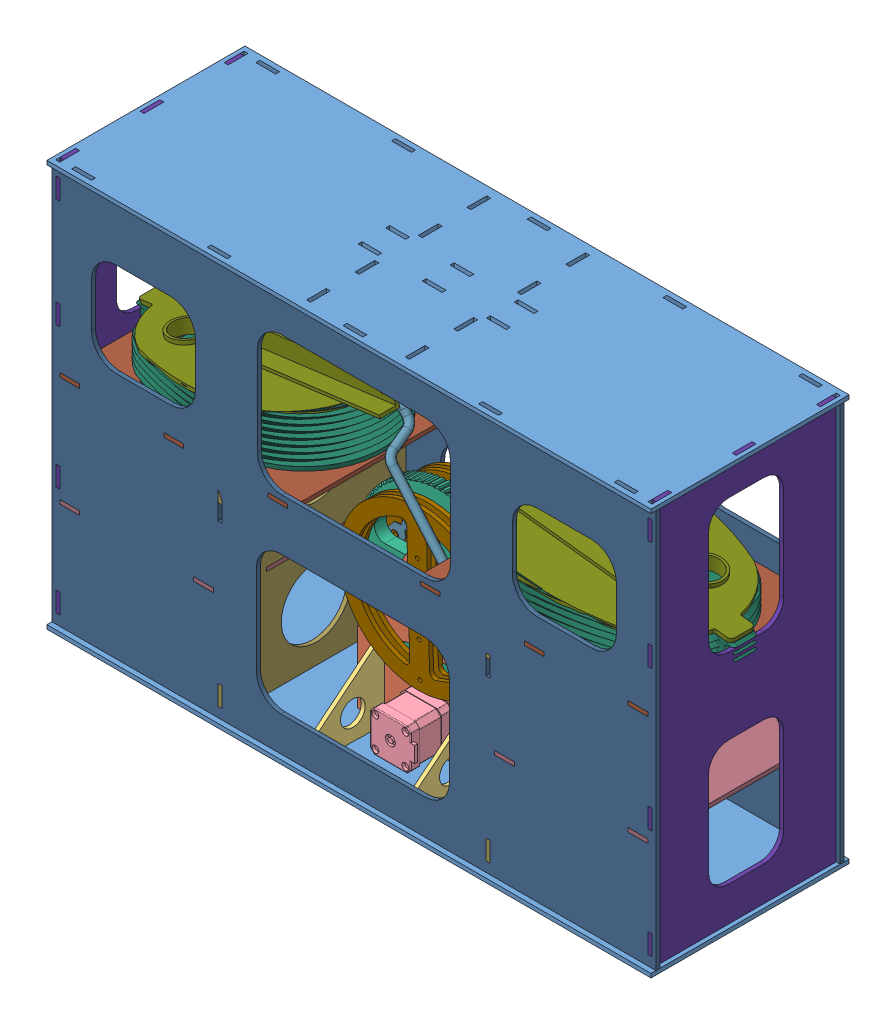
SolidWorks assembly ensamble definitivo, configuration Default. Lengths in mm.
Overall size (610 410 200).
34 component instances, 17 part files, 78 mates.
Components (placement in the parent):
- piso 2-1: piso 2 [Default] at (285.139 225.4546 499.656) size (610 4 200)
- frente de motor-1: frente de motor [Default] at (284.9987 229.3675 515.656) x (0 0 -1) z (1 0 0) size (4 174 150)
- lateral de motor-1: lateral de motor [Default] at (236.9987 266.8644 543.801) x (-1 0 0) z (0 0 -1) size (4 77.47 79)
- lateral de motor-2: lateral de motor [Default] at (336.9987 266.8644 543.801) x (-1 0 0) z (0 0 -1) size (4 77.47 79)
- nema 17-1: nema 17 [Default] at (284.9987 259.4546 557.656) x (0 0 -1) z (0 -1 0) size (62 45 41)
- pinon-1: pinon [Default] at (284.9987 259.4546 490.656) x (0 0 1) z (0.113847 0.993498 0) size (18 54.8 54.93)
- Corona-1: Corona [Default] at (284.9987 369.4546 494.656) x (0 0 1) z (0.025967 -0.999663 0) size (12 170.97 170.26)
- lateral de motor-3: lateral de motor [Default] at (332.9987 266.8644 455.5109) size (4 77.47 79)
- frente de motor-2: frente de motor [Default] at (284.9987 229.3675 483.656) x (0 0 1) z (-1 0 0) size (4 174 150)
- lateral de motor-4: lateral de motor [Default] at (232.9987 266.8644 455.5109) size (4 77.47 79)
- nema 17-2: nema 17 [Default] at (284.9987 259.4546 441.656) x (0 0 1) z (0 1 0) size (62 45 41)
- eje principal-1: eje principal [Default] at (284.9987 369.4546 461.656) x (-0.025967 0.999663 0) z (0 0 1) size (7.18 7.27 81.79)
- perno de eje-1: perno de eje [Default] at (294.9953 369.7143 501.656) x (-0.023397 0.900754 -0.4337) z (-0.011262 0.433554 0.901057) size (2.5 10 2.5)
- rueda-1: rueda [Default] at (284.9987 369.4546 520.656) x (0 0 -1) z (0.025967 -0.999663 0) size (4 160 160)
- rueda-2: rueda [Default] at (284.9987 369.4546 529.656) x (0 0 -1) z (0.025967 -0.999663 0) size (4 160 160)
- rueda-3: rueda [Default] at (284.9987 369.4546 478.656) x (0 0 1) z (-0.025967 0.999663 0) size (4 160 160)
- rueda-4: rueda [Default] at (284.9987 369.4546 469.656) x (0 0 1) z (-0.025967 0.999663 0) size (4 160 160)
- lateral-1: lateral [Default] at (381.7037 395.4546 404.656) x (0 0 1) z (-1 0 0) size (4 410 610)
- entrepiso-1: entrepiso [Default] at (464.639 447.4546 498.656) size (235 4 190)
- entrepiso-2: entrepiso [Default] at (105.639 447.4546 500.656) x (-1 0 0) z (0 0 -1) size (235 4 190)
- soporte de entrepiso-1: soporte de entrepiso [Default] at (418.529 367.4546 499.656) x (0 0 -1) z (0 -1 0) size (190 4 222)
- soporte de entrepiso-2: soporte de entrepiso [Default] at (151.749 367.4546 499.656) x (0 0 1) z (0 -1 0) size (190 4 222)
- piso para electronica-1: piso para electronica [Default] at (500.334 336.4546 499.656) size (163.61 4 190)
- piso para electronica-2: piso para electronica [Default] at (69.944 336.4546 499.656) x (-1 0 0) z (0 0 -1) size (163.61 4 190)
- piso 2-2: piso 2 [Default] at (285.139 631.4546 499.656) size (610 4 200)
- bastago-1: bastago [Default] at (269.488 426.4051 513.2183) x (0 0 -1) z (0.770429 -0.637526 0) size (38.86 205 15)
- tapa de fuelle2-1: tapa de fuelle2 [Default] at (457.139 451.4546 501.156) size (241.61 60.29 167.56)
- tapa sup de fuelle-1: tapa sup de fuelle [Default] at (460.122 485.6735 501.156) x (0.993467 -0.114119 0) z (0 0 1) size (265 43.89 160.08)
- tapa de fuelle2-2: tapa de fuelle2 [Default] at (113.139 451.4546 501.156) x (-1 0 0) z (0 0 -1) size (241.61 60.29 167.56)
- tapa sup de fuelle-2: tapa sup de fuelle [Default] at (109.7534 486.9893 501.156) x (-0.991646 -0.128987 0) z (0 0 -1) size (265 43.89 160.08)
- bastago-2: bastago [Default] at (300.2844 429.8311 500.156) x (0 0 1) z (-0.767978 -0.640476 0) size (38.86 205 15)
- frentes-1: frentes [Default] at (586.139 430.4546 499.656) x (0 0 1) z (-1 0 0) size (190 410 4)
- frentes-2: frentes [Default] at (-15.861 430.4546 499.656) x (0 0 -1) z (1 0 0) size (190 410 4)
- lateral-2: lateral [Default] at (381.7037 395.4546 590.656) x (0 0 1) z (-1 0 0) size (4 410 610)
Mates (geometry in assembly coordinates):
- Coincident1: coincident: plane of piso 2-1 through (359.9987 229.4546 511.656) normal (0 0 1); plane of frente de motor-1 through (284.9987 229.3675 511.656) normal (0 0 -1)
- Coincident2: coincident: plane of piso 2-1 through (359.9987 229.4546 515.656) normal (-1 0 0); plane of frente de motor-1 through (359.9987 225.4546 511.656) normal (1 0 0)
- Coincident3: coincident: plane of piso 2-1 through (285.139 229.4546 499.656) normal (0 1 0); plane of frente de motor-1 through (339.9987 229.4546 511.656) normal (0 -1 0)
- Coincident4: coincident: plane of frente de motor-1 through (284.9987 229.3675 515.656) normal (0 0 1); plane of lateral de motor-1 through (232.9987 280.9174 515.656) normal (0 0 -1)
- Coincident5: coincident: plane of frente de motor-1 through (232.9987 280.9174 511.656) normal (1 0 0); plane of lateral de motor-1 through (232.9987 266.8644 543.801) normal (-1 0 0)
- Coincident6: coincident: plane of piso 2-1 through (285.139 229.4546 499.656) normal (0 1 0); plane of lateral de motor-1 through (232.9987 229.4546 541.656) normal (0 -1 0)
- Coincident7: coincident: plane of frente de motor-1 through (332.9987 300.9174 511.656) normal (1 0 0); plane of lateral de motor-2 through (332.9987 266.8644 543.801) normal (-1 0 0)
- Coincident8: coincident: plane of frente de motor-1 through (284.9987 229.3675 515.656) normal (0 0 1); plane of lateral de motor-2 through (332.9987 280.9174 515.656) normal (0 0 -1)
- Coincident9: coincident: plane of piso 2-1 through (285.139 229.4546 499.656) normal (0 1 0); plane of lateral de motor-2 through (332.9987 229.4546 541.656) normal (0 -1 0)
- Concentric1: concentric: cylinder of frente de motor-1 through (284.9987 259.4546 511.656) axis (0 0 1) radius 11; cylinder of nema 17-1 through (284.9987 259.4546 512.656) axis (0 0 1) radius 11
- Concentric2: concentric: cylinder of frente de motor-1 through (300.9086 243.5447 511.656) axis (0 0 1) radius 1.75; cylinder of nema 17-1 through (300.9086 243.5447 519.656) axis (0 0 -1) radius 1.5
- Coincident10: coincident: plane of frente de motor-1 through (284.9987 229.3675 515.656) normal (0 0 1); plane of nema 17-1 through (284.9987 259.4546 515.656) normal (0 0 -1)
- Concentric3: concentric: cylinder of nema 17-1 through (284.9987 259.4546 495.656) axis (0 0 1) radius 2.5; cylinder of pinon-1 through (284.9987 259.4546 508.656) axis (0 0 -1) radius 2.5
- Distance1: distance = 3 mm: plane of pinon-1 through (284.9987 259.4546 508.656) normal (0 0 1); plane of frente de motor-1 through (284.9987 229.3675 511.656) normal (0 0 -1)
- Concentric4: concentric: cylinder of frente de motor-1 through (284.9987 369.4546 511.656) axis (0 0 1) radius 10; cylinder of Corona-1 through (284.9987 369.4546 506.656) axis (0 0 -1) radius 3.5
- Distance2: distance = 5 mm: plane of Corona-1 through (284.9987 369.4546 506.656) normal (0 0 1); plane of frente de motor-1 through (284.9987 229.3675 511.656) normal (0 0 -1)
- GearMate1: gear = 165 : 49 mm: cylinder of pinon-1 through (284.9987 259.4546 508.656) axis (0 0 -1) radius 24.5; cylinder of Corona-1 through (284.9987 369.4546 506.656) axis (0 0 -1) radius 82.5
- Concentric6: concentric: cylinder of Corona-1 through (284.9987 369.4546 506.656) axis (0 0 -1) radius 3.5; cylinder of eje principal-1 through (284.9987 369.4546 541.656) axis (0 0 -1) radius 3.5
- Concentric7: concentric: cylinder of eje principal-1 through (277.0639 363.3687 501.656) axis (0.793481 0.608594 0) radius 1.25; cylinder of perno de eje-1 through (284.9987 369.4546 501.656) axis (0.793481 0.608594 0) radius 1.25
- Coincident13: coincident: plane of Corona-1 through (293.6942 374.5487 494.656) normal (-0.793481 -0.608594 0); plane of perno de eje-1 through (292.9335 375.5406 501.656) normal (0.793481 0.608594 0)
- Distance4: distance = 35 mm: plane of eje principal-1 through (284.9987 369.4546 541.656) normal (0 0 1); plane of Corona-1 through (284.9987 369.4546 506.656) normal (0 0 1)
- Concentric9: concentric: cylinder of eje principal-1 through (284.9987 369.4546 541.656) axis (0 0 -1) radius 3.5; cylinder of rueda-1 through (284.9987 369.4546 516.656) axis (0 0 1) radius 3
- Distance5: distance = 1 mm: plane of rueda-1 through (284.9987 369.4546 516.656) normal (0 0 -1); plane of frente de motor-1 through (284.9987 229.3675 515.656) normal (0 0 1)
- Concentric10: concentric: cylinder of eje principal-1 through (284.9987 369.4546 541.656) axis (0 0 -1) radius 3.5; cylinder of rueda-2 through (284.9987 369.4546 525.656) axis (0 0 1) radius 3
- Distance6: distance = 5 mm: plane of rueda-2 through (284.9987 369.4546 525.656) normal (0 0 -1); plane of rueda-1 through (284.9987 369.4546 520.656) normal (0 0 1)
- Coincident17: coincident: plane of Corona-1 through (293.6942 374.5487 494.656) normal (-0.608594 0.793481 0); plane of rueda-1 through (281.792 365.4198 510.656) normal (-0.608594 0.793481 0)
- Coincident18: coincident: plane of rueda-1 through (281.792 365.4198 510.656) normal (-0.608594 0.793481 0); plane of rueda-2 through (281.792 365.4198 519.656) normal (-0.608594 0.793481 0)
- Parallel2: parallel: plane of piso 2-1 through (-19.861 229.4546 399.656) normal (0 0 -1); plane of lateral-1 through (381.7037 395.4546 404.656) normal (0 0 -1)
- Coincident22: coincident: plane of piso 2-1 through (568.139 229.4546 408.656) normal (-1 0 0); plane of lateral-1 through (568.139 225.4546 408.656) normal (1 0 0)
- Coincident23: coincident: plane of piso 2-1 through (285.139 229.4546 499.656) normal (0 1 0); plane of lateral-1 through (431.139 229.4546 408.656) normal (0 -1 0)
- Coincident24: coincident: plane of piso 2-1 through (548.139 229.4546 404.656) normal (0 0 1); plane of lateral-1 through (381.7037 395.4546 404.656) normal (0 0 -1)
- Coincident25: coincident: plane of lateral-1 through (477.139 451.4546 408.656) normal (0 -1 0); plane of entrepiso-1 through (464.639 451.4546 498.656) normal (0 1 0)
- Coincident26: coincident: plane of lateral-1 through (582.139 451.4546 408.656) normal (-1 0 0); plane of entrepiso-1 through (582.139 451.4546 404.656) normal (1 0 0)
- Coincident27: coincident: plane of lateral-1 through (381.7037 395.4546 408.656) normal (0 0 1); plane of entrepiso-1 through (477.139 451.4546 408.656) normal (0 0 -1)
- Coincident28: coincident: plane of lateral-1 through (381.7037 395.4546 408.656) normal (0 0 1); plane of entrepiso-2 through (198.139 451.4546 408.656) normal (0 0 -1)
- Coincident29: coincident: plane of lateral-1 through (93.139 451.4546 408.656) normal (0 -1 0); plane of entrepiso-2 through (105.639 451.4546 500.656) normal (0 1 0)
- Coincident31: coincident: plane of lateral-1 through (218.139 451.4546 408.656) normal (-1 0 0); plane of entrepiso-2 through (218.139 451.4546 408.656) normal (1 0 0)
- Coincident32: coincident: plane of piso 2-1 through (285.139 229.4546 499.656) normal (0 1 0); plane of soporte de entrepiso-1 through (422.529 229.4546 590.656) normal (0 -1 0)
- Coincident33: coincident: plane of lateral-1 through (381.7037 395.4546 408.656) normal (0 0 1); plane of soporte de entrepiso-1 through (422.529 259.4546 408.656) normal (0 0 -1)
- Coincident34: coincident: plane of entrepiso-1 through (422.529 451.4546 449.656) normal (-1 0 0); plane of soporte de entrepiso-1 through (422.529 367.4546 499.656) normal (1 0 0)
- Coincident35: coincident: plane of piso 2-1 through (285.139 229.4546 499.656) normal (0 1 0); plane of soporte de entrepiso-2 through (147.749 229.4546 408.656) normal (0 -1 0)
- Coincident36: coincident: plane of lateral-1 through (381.7037 395.4546 408.656) normal (0 0 1); plane of soporte de entrepiso-2 through (147.749 259.4546 408.656) normal (0 0 -1)
- Coincident37: coincident: plane of entrepiso-2 through (147.749 451.4546 549.656) normal (1 0 0); plane of soporte de entrepiso-2 through (147.749 367.4546 499.656) normal (-1 0 0)
- Coincident38: coincident: plane of soporte de entrepiso-1 through (422.529 340.4546 549.656) normal (0 -1 0); plane of piso para electronica-1 through (500.334 340.4546 499.656) normal (0 1 0)
- Coincident41: coincident: plane of soporte de entrepiso-1 through (422.529 340.4546 549.656) normal (0 0 -1); plane of piso para electronica-1 through (418.529 340.4546 549.656) normal (0 0 1)
- Coincident42: coincident: plane of soporte de entrepiso-1 through (422.529 367.4546 499.656) normal (1 0 0); plane of piso para electronica-1 through (422.529 340.4546 590.656) normal (-1 0 0)
- Coincident43: coincident: plane of soporte de entrepiso-2 through (147.749 340.4546 449.656) normal (0 -1 0); plane of piso para electronica-2 through (69.944 340.4546 499.656) normal (0 1 0)
- Coincident44: coincident: plane of lateral-1 through (381.7037 395.4546 408.656) normal (0 0 1); plane of piso para electronica-2 through (123.1433 340.4546 408.656) normal (0 0 -1)
- Coincident45: coincident: plane of soporte de entrepiso-2 through (151.749 367.4546 499.656) normal (1 0 0); plane of piso para electronica-2 through (151.749 340.4546 449.656) normal (1 0 0)
- Coincident46: coincident: plane of lateral-1 through (381.7037 395.4546 404.656) normal (0 0 -1); plane of piso 2-2 through (548.139 635.4546 404.656) normal (0 0 1)
- Coincident47: coincident: plane of lateral-1 through (431.139 631.4546 408.656) normal (0 1 0); plane of piso 2-2 through (285.139 631.4546 499.656) normal (0 -1 0)
- Coincident48: coincident: plane of lateral-1 through (568.139 631.4546 408.656) normal (1 0 0); plane of piso 2-2 through (568.139 635.4546 408.656) normal (-1 0 0)
- Concentric12: concentric: cylinder of rueda-4 through (229.455 326.853 473.656) axis (0 0 -1) radius 2; cylinder of bastago-1 through (229.455 326.853 475.2183) axis (0 0 1) radius 3.8245
- Coincident55: coincident: plane of entrepiso-1 through (464.639 451.4546 498.656) normal (0 1 0); plane of tapa de fuelle2-1 through (435.525 451.4546 685.5205) normal (0 -1 0)
- Coincident56: coincident: plane of entrepiso-1 through (582.139 451.4546 404.656) normal (1 0 0); plane of tapa de fuelle2-1 through (582.139 455.4546 492.656) normal (1 0 0)
- Distance10: distance = 80 mm: plane of tapa de fuelle2-1 through (567.7968 455.4546 488.656) normal (0 0 -1); plane of lateral-1 through (381.7037 395.4546 408.656) normal (0 0 1)
- Concentric13: concentric: cylinder of tapa de fuelle2-1 through (548.1663 459.4546 556.156) axis (0 0 -1) radius 2; cylinder of tapa sup de fuelle-1 through (548.1663 459.4546 467.156) axis (0 0 1) radius 2
- Coincident58: coincident: plane of tapa de fuelle2-1 through (545.1663 463.4546 476.156) normal (0 0 1); plane of tapa sup de fuelle-1 through (545.2042 455.4265 476.156) normal (0 0 -1)
- Concentric14: concentric: cylinder of bastago-1 through (331.0332 487.4204 505.2183) axis (0 0 1) radius 3.8245; cylinder of tapa sup de fuelle-1 through (331.0332 487.4204 466.156) axis (0 0 1) radius 2
- Coincident59: coincident: plane of entrepiso-2 through (105.639 451.4546 500.656) normal (0 1 0); plane of tapa de fuelle2-2 through (134.753 451.4546 316.7914) normal (0 -1 0)
- Coincident60: coincident: plane of entrepiso-2 through (-11.861 451.4546 594.656) normal (-1 0 0); plane of tapa de fuelle2-2 through (-11.861 455.4546 509.656) normal (-1 0 0)
- Distance11: distance = 80 mm: plane of tapa de fuelle2-2 through (-7.861 455.4546 488.656) normal (0 0 -1); plane of lateral-1 through (381.7037 395.4546 408.656) normal (0 0 1)
- Concentric15: concentric: cylinder of tapa de fuelle2-2 through (22.1116 459.4546 446.156) axis (0 0 1) radius 2; cylinder of tapa sup de fuelle-2 through (22.1116 459.4546 535.156) axis (0 0 -1) radius 2
- Coincident61: coincident: plane of tapa de fuelle2-2 through (25.1116 463.4546 476.156) normal (0 0 1); plane of tapa sup de fuelle-2 through (26.2333 456.6241 476.156) normal (0 0 -1)
- Concentric16: concentric: cylinder of tapa sup de fuelle-2 through (217.9843 557.2441 536.156) axis (0 0 -1) radius 2; cylinder of bastago-2 through (217.9843 557.2441 508.156) axis (0 0 -1) radius 3.8245
- Distance13: distance = 3 mm: plane of bastago-2 through (233.2879 517.1909 508.156) normal (0 0 1); plane of tapa sup de fuelle-2 through (69.9649 506.0311 511.156) normal (0 0 -1)
- Concentric17: concentric: cylinder of rueda-2 through (340.5424 412.0563 525.656) axis (0 0 1) radius 2; cylinder of bastago-2 through (340.5424 412.0563 538.156) axis (0 0 -1) radius 3.8245
- Coincident64: coincident: plane of lateral-1 through (381.7037 395.4546 408.656) normal (0 0 1); plane of frentes-1 through (582.139 430.4546 408.656) normal (0 0 -1)
- Coincident65: coincident: plane of piso 2-2 through (285.139 631.4546 499.656) normal (0 -1 0); plane of frentes-1 through (582.139 631.4546 499.656) normal (0 1 0)
- Coincident66: coincident: plane of piso 2-2 through (586.139 635.4546 594.656) normal (-1 0 0); plane of frentes-1 through (586.139 430.4546 499.656) normal (1 0 0)
- Coincident67: coincident: plane of lateral-1 through (-11.861 511.4546 408.656) normal (-1 0 0); plane of frentes-2 through (-11.861 430.4546 499.656) normal (1 0 0)
- Coincident68: coincident: plane of piso 2-2 through (-15.861 635.4546 594.656) normal (1 0 0); plane of frentes-2 through (-15.861 430.4546 499.656) normal (-1 0 0)
- Coincident69: coincident: plane of lateral-1 through (381.7037 395.4546 408.656) normal (0 0 1); plane of frentes-2 through (-11.861 430.4546 408.656) normal (0 0 -1)
- Coincident70: coincident: plane of piso 2-2 through (285.139 631.4546 499.656) normal (0 -1 0); plane of frentes-2 through (-11.861 631.4546 499.656) normal (0 1 0)
- Parallel4: parallel: plane of lateral-2 through (381.7037 395.4546 594.656) normal (0 0 1); plane of piso 2-1 through (-19.861 229.4546 599.656) normal (0 0 1)
- Coincident71: coincident: plane of piso 2-1 through (285.139 229.4546 499.656) normal (0 1 0); plane of lateral-2 through (20.139 229.4546 594.656) normal (0 -1 0)
- Coincident72: coincident: plane of piso 2-1 through (20.139 229.4546 594.656) normal (0 0 -1); plane of lateral-2 through (381.7037 395.4546 594.656) normal (0 0 1)
- Coincident73: coincident: plane of piso 2-1 through (0.139 229.4546 590.656) normal (1 0 0); plane of lateral-2 through (0.139 229.4546 594.656) normal (-1 0 0)
